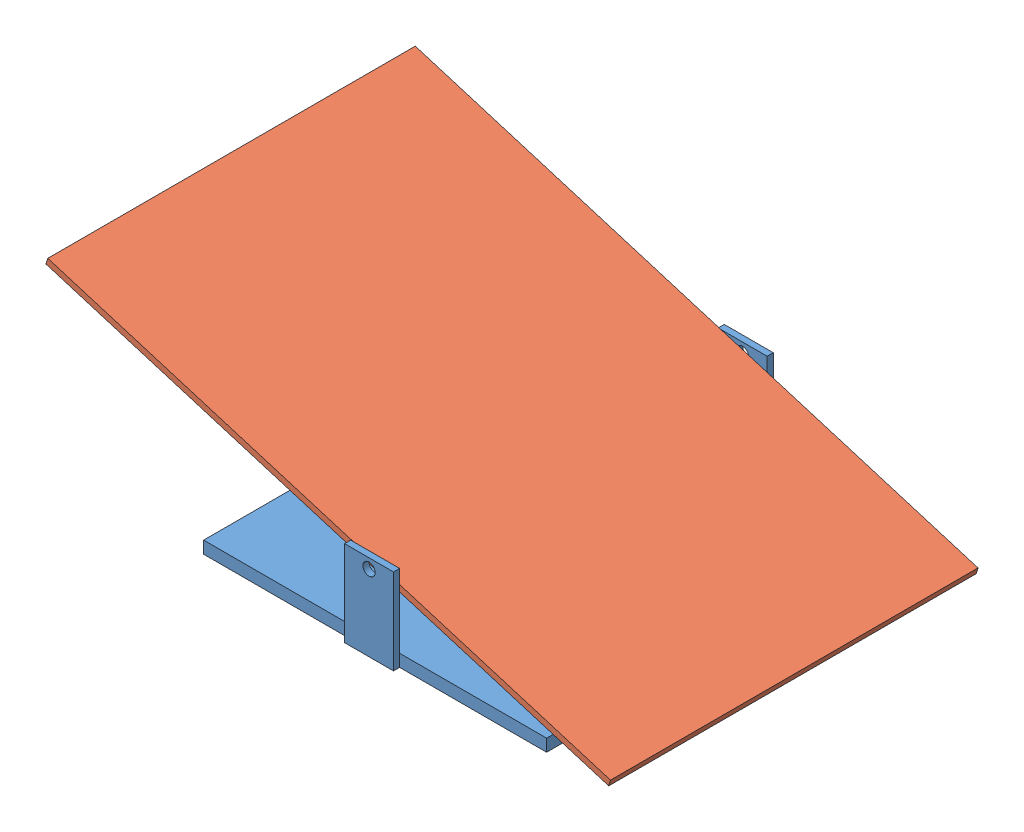
SolidWorks assembly See-saw, configuration Default. Lengths in mm.
Overall size (460.82 145.6 310).
2 component instances, 2 part files, 2 mates.
Components (placement in the parent):
- Base-1: Base [Default] at origin size (280 70 310)
- MovingPart^See-saw-1: MovingPart^See-saw [Default] at (-127.2398 145.6012 0) x (0.957017 -0.290031 0) z (0 0 1) size (480 5 300) (virtual)
Mates (geometry in assembly coordinates):
- Concentric1: concentric anti-aligned: cylinder of MovingPart^See-saw-1 through (140 62 -300) axis (0 0 1) radius 2; line of assembly
- Coincident1: coincident anti-aligned: plane of Base-1 through (0 0 0) normal (0 0 -1); plane of MovingPart^See-saw-1 through (-128.6899 140.8161 0) normal (0 0 1)
